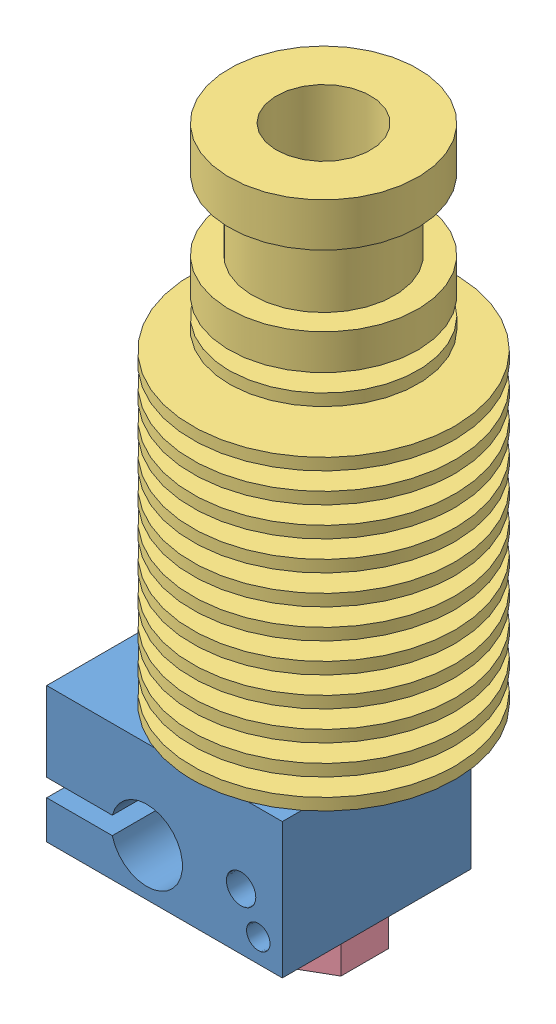
SolidWorks assembly Assem1, configuration Default. Lengths in mm.
Overall size (26.95 61.85 22.9).
4 component instances, 4 part files, 6 mates.
Components (placement in the parent):
- V6-BLOCK-1: V6-BLOCK [Default] at (3.1723 13.0752 15.8249) size (20 12.14 16)
- V6-175-BREAK-1: V6-175-BREAK [Default] at (8.6723 14.5752 15.8249) size (6.95 22.4 6.95)
- V6-175-SINK-1: V6-175-SINK [Default] at (8.6723 42.5778 15.8249) x (0.999633 0 0.027082) z (-0.027082 0 0.999633) size (22.3 42.99 22.3)
- V6-NOZZLE-175-035-1: V6-NOZZLE-175-035 [Default] at (8.6723 2.0752 15.8249) size (7 12.82 8.08)
Mates (geometry in assembly coordinates):
- Concentric1: concentric anti-aligned: cylinder of V6-175-BREAK-1 through (8.6723 7.5585 15.8249) axis (0 -1 0) radius 2.825; cylinder of V6-175-SINK-1 through (8.6723 57.1778 15.8249) axis (0 1 0) radius 4
- Coincident1: coincident: circle of V6-175-BREAK-1; cone of V6-175-SINK-1 through (8.6723 35.8551 15.8249) axis (0 1 0)
- Concentric4: concentric anti-aligned: cylinder of V6-BLOCK-1 through (8.6723 7.3242 15.8249) axis (0 1 0) radius 2.5; cylinder of V6-175-BREAK-1 through (8.6723 7.5585 15.8249) axis (0 -1 0) radius 1.4
- Coincident6: coincident anti-aligned: plane of V6-175-BREAK-1 through (8.6723 13.8252 15.8249) normal (0 -1 0); plane of V6-NOZZLE-175-035-1 through (8.6723 13.8252 15.8249) normal (0 1 0)
- Concentric5: concentric anti-aligned: cylinder of V6-BLOCK-1 through (8.6723 7.3242 15.8249) axis (0 1 0) radius 2.5; cone of V6-NOZZLE-175-035-1 through (8.6723 14.137 15.8249) axis (0 -1 0)
- Distance1: distance = 0.25 mm anti-aligned: plane of V6-NOZZLE-175-035-1 through (6.1723 7.0752 15.8249) normal (0 1 0); plane of V6-BLOCK-1 through (3.1723 7.3252 15.8249) normal (0 -1 0)
